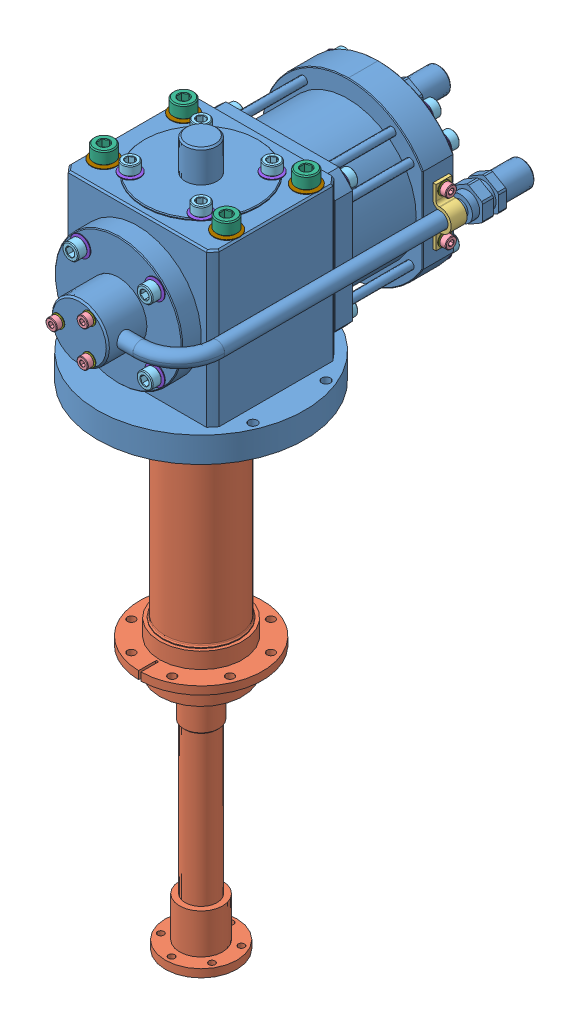
SolidWorks assembly SRDK-101D, configuration Default. Lengths in mm.
Overall size (130 442 230.94).
77 component instances, 9 part files, 0 mates.
Components (placement in the parent):
- SRDK-101D-01-1: SRDK-101D-01 [Default] at (0 517.452 187.325) size (130 133.2 226.3)
- SRDK-101D-02-1: SRDK-101D-02 [Default] at (0 517.452 187.325) size (81.34 308.8 81.03)
- SRDK-101D-03-1: SRDK-101D-03 [Default] at (52 581.652 84.425) size (12.07 36 10)
- HARDWARE_1-1: HARDWARE_1 [Default] at (-13 581.652 256.425) x (0.923728 0.383049 0) z (0 0 -1) size (7 7 12.04)
- HARDWARE_1-2: HARDWARE_1 [Default] at (42.1 595.652 84.425) x (0 0 1) z (-1 0 0) size (7 7 12.04)
- HARDWARE_1-3: HARDWARE_1 [Default] at (-9.5459 616.1979 80.925) size (7 7 12.04)
- HARDWARE_1-4: HARDWARE_1 [Default] at (-11.5 565.752 81.275) size (7 7 12.04)
- HARDWARE_2-1: HARDWARE_2 [Default] at (-22.2739 623.502 209.5989) x (1 0 0) z (0 -1 0) size (10 10 14.07)
- HARDWARE_2-2: HARDWARE_2 [Default] at (-27.8095 620.7753 82.975) size (10 10 14.07)
- HARDWARE_2-3: HARDWARE_2 [Default] at (-23.3345 604.9865 232.175) x (0.923728 0.383049 0) z (0 0 -1) size (10 10 14.07)
- HARDWARE_2-4: HARDWARE_2 [Default] at (-35.3553 617.0073 142.975) x (0.328464 0.944516 0) z (0 0 1) size (10 10 14.07)
- HARDWARE_3-1: HARDWARE_3 [Default] at (-38.5 618.552 209.825) x (1 0 0) z (0 -1 0) size (13 13 20.09)
- HARDWARE_4-1: HARDWARE_4 [Default] at (-13 581.652 263.825) x (-0.923728 -0.383049 0) z (-0.383049 0.923728 0) size (8 0.6 8)
- HARDWARE_4-2: HARDWARE_4 [Default] at (-11.5 565.752 73.875) x (1 0 0) z (0 1 0) size (8 0.6 8)
- HARDWARE_4-3: HARDWARE_4 [Default] at (-9.5459 616.1979 73.525) x (1 0 0) z (0 1 0) size (8 0.6 8)
- HARDWARE_4-4: HARDWARE_4 [Default] at (49.5 595.652 84.425) x (0 0 1) z (0 1 0) size (8 0.6 8)
- HARDWARE_5-1: HARDWARE_5 [Default] at (-23.3345 604.9865 239.325) x (-0.923728 -0.383049 0) z (-0.383049 0.923728 0) size (12.5 0.85 12.5)
- HARDWARE_5-2: HARDWARE_5 [Default] at (-35.3553 617.0073 135.825) x (1 0 0) z (0 1 0) size (12.5 0.85 12.5)
- HARDWARE_5-3: HARDWARE_5 [Default] at (-22.2739 630.652 209.5989) size (12.5 0.85 12.5)
- HARDWARE_5-4: HARDWARE_5 [Default] at (-27.8095 620.7753 75.825) x (1 0 0) z (0 1 0) size (12.5 0.85 12.5)
- HARDWARE_6-1: HARDWARE_6 [Default] at (-38.5 629.652 209.825) size (16 0.9 16)
- HARDWARE_1-5: HARDWARE_1 [Default] at (6.5 570.3937 256.425) x (-0.793594 0.608447 0) z (0 0 -1) size (7 7 12.04)
- HARDWARE_1-6: HARDWARE_1 [Default] at (6.5 592.9103 256.425) x (-0.130134 -0.991496 0) z (0 0 -1) size (7 7 12.04)
- HARDWARE_4-5: HARDWARE_4 [Default] at (6.5 570.3937 263.825) x (0.793594 -0.608447 0) z (-0.608447 -0.793594 0) size (8 0.6 8)
- HARDWARE_4-6: HARDWARE_4 [Default] at (6.5 592.9103 263.825) x (0.130134 0.991496 0) z (0.991496 -0.130134 0) size (8 0.6 8)
- HARDWARE_2-5: HARDWARE_2 [Default] at (-23.3345 558.3175 232.175) x (-0.383049 0.923728 0) z (0 0 -1) size (10 10 14.07)
- HARDWARE_2-6: HARDWARE_2 [Default] at (23.3345 558.3175 232.175) x (-0.923728 -0.383049 0) z (0 0 -1) size (10 10 14.07)
- HARDWARE_2-7: HARDWARE_2 [Default] at (23.3345 604.9865 232.175) x (0.383049 -0.923728 0) z (0 0 -1) size (10 10 14.07)
- HARDWARE_5-5: HARDWARE_5 [Default] at (-23.3345 558.3175 239.325) x (0.383049 -0.923728 0) z (-0.923728 -0.383049 0) size (12.5 0.85 12.5)
- HARDWARE_5-6: HARDWARE_5 [Default] at (23.3345 558.3175 239.325) x (0.923728 0.383049 0) z (0.383049 -0.923728 0) size (12.5 0.85 12.5)
- HARDWARE_5-7: HARDWARE_5 [Default] at (23.3345 604.9865 239.325) x (-0.383049 0.923728 0) z (0.923728 0.383049 0) size (12.5 0.85 12.5)
- HARDWARE_5-8: HARDWARE_5 [Default] at (22.2739 630.652 209.5989) x (0 0 -1) z (1 0 0) size (12.5 0.85 12.5)
- HARDWARE_5-9: HARDWARE_5 [Default] at (22.2739 630.652 165.0511) x (-1 0 0) z (0 0 -1) size (12.5 0.85 12.5)
- HARDWARE_5-10: HARDWARE_5 [Default] at (-22.2739 630.652 165.0511) x (0 0 1) z (-1 0 0) size (12.5 0.85 12.5)
- HARDWARE_2-8: HARDWARE_2 [Default] at (22.2739 623.502 209.5989) x (0 0 -1) z (0 -1 0) size (10 10 14.07)
- HARDWARE_2-9: HARDWARE_2 [Default] at (22.2739 623.502 165.0511) x (-1 0 0) z (0 -1 0) size (10 10 14.07)
- HARDWARE_2-10: HARDWARE_2 [Default] at (-22.2739 623.502 165.0511) x (0 0 1) z (0 -1 0) size (10 10 14.07)
- HARDWARE_6-2: HARDWARE_6 [Default] at (38.5 629.652 209.825) size (16 0.9 16)
- HARDWARE_6-3: HARDWARE_6 [Default] at (-38.5 629.652 159.825) size (16 0.9 16)
- HARDWARE_6-4: HARDWARE_6 [Default] at (38.5 629.652 159.825) size (16 0.9 16)
- HARDWARE_3-2: HARDWARE_3 [Default] at (38.5 618.552 209.825) x (1 0 0) z (0 -1 0) size (13 13 20.09)
- HARDWARE_3-3: HARDWARE_3 [Default] at (-38.5 618.552 159.825) x (1 0 0) z (0 -1 0) size (13 13 20.09)
- HARDWARE_3-4: HARDWARE_3 [Default] at (38.5 618.552 159.825) x (1 0 0) z (0 -1 0) size (13 13 20.09)
- HARDWARE_4-7: HARDWARE_4 [Default] at (9.5459 616.1979 73.525) x (0 -1 0) z (1 0 0) size (8 0.6 8)
- HARDWARE_4-8: HARDWARE_4 [Default] at (9.5459 597.1061 73.525) x (-1 0 0) z (0 -1 0) size (8 0.6 8)
- HARDWARE_4-9: HARDWARE_4 [Default] at (-9.5459 597.1061 73.525) x (0 1 0) z (-1 0 0) size (8 0.6 8)
- HARDWARE_1-7: HARDWARE_1 [Default] at (9.5459 616.1979 80.925) x (0 -1 0) z (0 0 1) size (7 7 12.04)
- HARDWARE_1-8: HARDWARE_1 [Default] at (9.5459 597.1061 80.925) x (-1 0 0) z (0 0 1) size (7 7 12.04)
- HARDWARE_1-9: HARDWARE_1 [Default] at (-9.5459 597.1061 80.925) x (0 1 0) z (0 0 1) size (7 7 12.04)
- HARDWARE_4-10: HARDWARE_4 [Default] at (11.5 565.752 73.875) x (0 -1 0) z (1 0 0) size (8 0.6 8)
- HARDWARE_4-11: HARDWARE_4 [Default] at (11.5 542.752 73.875) x (-1 0 0) z (0 -1 0) size (8 0.6 8)
- HARDWARE_4-12: HARDWARE_4 [Default] at (-11.5 542.752 73.875) x (0 1 0) z (-1 0 0) size (8 0.6 8)
- HARDWARE_1-10: HARDWARE_1 [Default] at (11.5 565.752 81.275) x (0 -1 0) z (0 0 1) size (7 7 12.04)
- HARDWARE_1-11: HARDWARE_1 [Default] at (11.5 542.752 81.275) x (-1 0 0) z (0 0 1) size (7 7 12.04)
- HARDWARE_1-12: HARDWARE_1 [Default] at (-11.5 542.752 81.275) x (0 1 0) z (0 0 1) size (7 7 12.04)
- HARDWARE_5-11: HARDWARE_5 [Default] at (-35.3553 546.2967 135.825) x (0 1 0) z (-1 0 0) size (12.5 0.85 12.5)
- HARDWARE_5-12: HARDWARE_5 [Default] at (35.3553 546.2967 135.825) x (-1 0 0) z (0 -1 0) size (12.5 0.85 12.5)
- HARDWARE_5-13: HARDWARE_5 [Default] at (35.3553 617.0073 135.825) x (0 -1 0) z (1 0 0) size (12.5 0.85 12.5)
- HARDWARE_2-11: HARDWARE_2 [Default] at (-35.3553 546.2967 142.975) x (-0.944516 0.328464 0) z (0 0 1) size (10 10 14.07)
- HARDWARE_2-12: HARDWARE_2 [Default] at (35.3553 546.2967 142.975) x (-0.328464 -0.944516 0) z (0 0 1) size (10 10 14.07)
- HARDWARE_2-13: HARDWARE_2 [Default] at (35.3553 617.0073 142.975) x (0.944516 -0.328464 0) z (0 0 1) size (10 10 14.07)
- HARDWARE_4-13: HARDWARE_4 [Default] at (49.5 567.652 84.425) x (0 0 1) z (0 1 0) size (8 0.6 8)
- HARDWARE_1-13: HARDWARE_1 [Default] at (42.1 567.652 84.425) x (0 0 1) z (-1 0 0) size (7 7 12.04)
- HARDWARE_5-14: HARDWARE_5 [Default] at (39.1233 609.4615 75.825) x (0 -1 0) z (1 0 0) size (12.5 0.85 12.5)
- HARDWARE_5-15: HARDWARE_5 [Default] at (27.8095 542.5287 75.825) x (-1 0 0) z (0 -1 0) size (12.5 0.85 12.5)
- HARDWARE_5-16: HARDWARE_5 [Default] at (-39.1233 553.8425 75.825) x (0 1 0) z (-1 0 0) size (12.5 0.85 12.5)
- HARDWARE_2-14: HARDWARE_2 [Default] at (39.1233 609.4615 82.975) x (0 -1 0) z (0 0 1) size (10 10 14.07)
- HARDWARE_2-15: HARDWARE_2 [Default] at (27.8095 542.5287 82.975) x (-1 0 0) z (0 0 1) size (10 10 14.07)
- HARDWARE_2-16: HARDWARE_2 [Default] at (-39.1233 553.8425 82.975) x (0 1 0) z (0 0 1) size (10 10 14.07)
- HARDWARE_5-17: HARDWARE_5 [Default] at (-39.1533 609.4193 75.825) x (0.944089 0.329691 0) z (-0.329691 0.944089 0) size (12.5 0.85 12.5)
- HARDWARE_2-17: HARDWARE_2 [Default] at (-39.1533 609.4193 82.975) x (0.944089 0.329691 0) z (0 0 1) size (10 10 14.07)
- HARDWARE_5-18: HARDWARE_5 [Default] at (27.7673 620.8053 75.825) x (0.329691 -0.944089 0) z (0.944089 0.329691 0) size (12.5 0.85 12.5)
- HARDWARE_5-19: HARDWARE_5 [Default] at (39.1533 553.8847 75.825) x (-0.944089 -0.329691 0) z (0.329691 -0.944089 0) size (12.5 0.85 12.5)
- HARDWARE_5-20: HARDWARE_5 [Default] at (-27.7673 542.4987 75.825) x (-0.329691 0.944089 0) z (-0.944089 -0.329691 0) size (12.5 0.85 12.5)
- HARDWARE_2-18: HARDWARE_2 [Default] at (27.7673 620.8053 82.975) x (0.329691 -0.944089 0) z (0 0 1) size (10 10 14.07)
- HARDWARE_2-19: HARDWARE_2 [Default] at (39.1533 553.8847 82.975) x (-0.944089 -0.329691 0) z (0 0 1) size (10 10 14.07)
- HARDWARE_2-20: HARDWARE_2 [Default] at (-27.7673 542.4987 82.975) x (-0.329691 0.944089 0) z (0 0 1) size (10 10 14.07)
